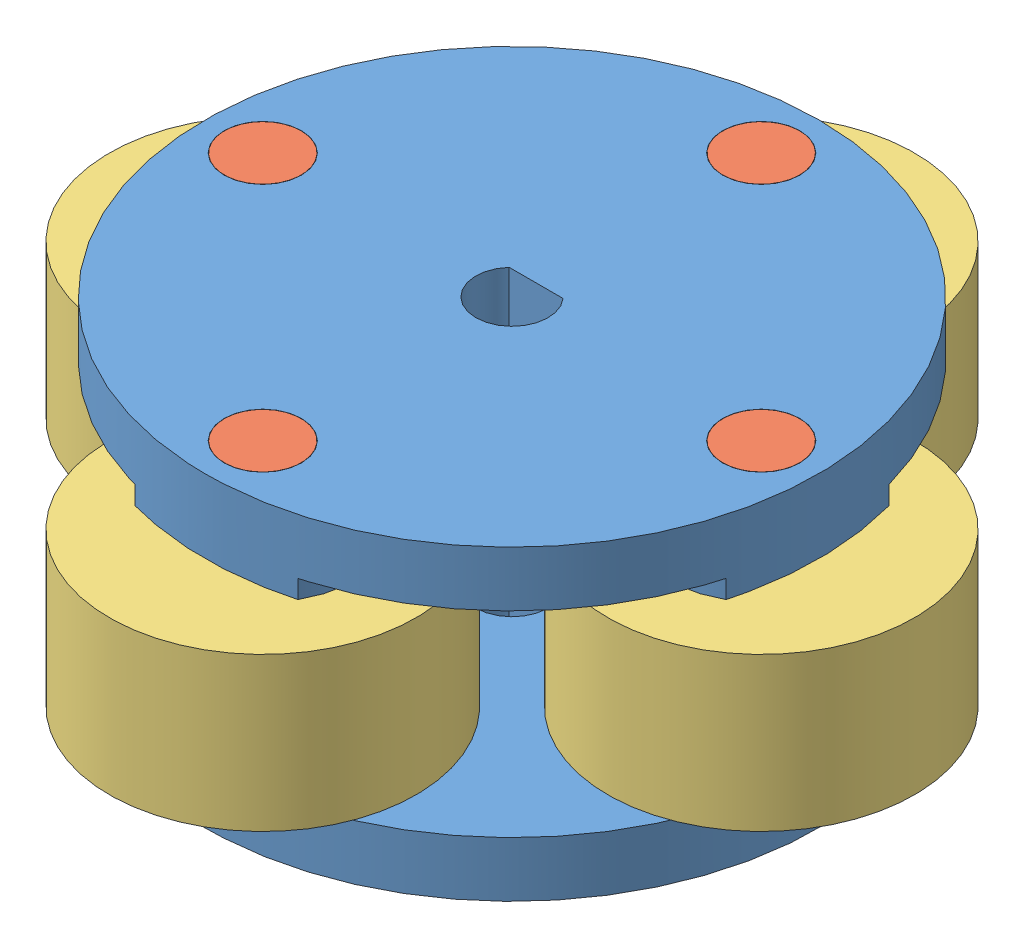
SolidWorks assembly Pump Assy, configuration Default. Lengths in mm.
Overall size (40.83 14.61 40.83).
14 component instances, 3 part files, 8 mates.
Components (placement in the parent):
- Wheel-1: Wheel [Default] at origin size (25.4 4 25.4)
- Roller Assembly-1: Roller Assembly [Default] at (-10.3187 6.35 0) x (0.813985 0 0.580886) z (-0.580886 0 0.813985) size (16.81 12.7 16.81)
  - dowel-1: dowel [Default] at origin size (3.17 12.7 3.17)
  - Sleeve Bearing-1: Sleeve Bearing [Default] x (0.980576 0 0.196139) z (-0.196139 0 0.980576) size (14.29 6.35 14.29)
- Roller Assembly-2: Roller Assembly [Default] at (0 6.35 -10.3187) x (-0.580886 0 0.813985) z (-0.813985 0 -0.580886) size (16.81 12.7 16.81)
  - dowel-1: dowel [Default] at origin size (3.17 12.7 3.17)
  - Sleeve Bearing-1: Sleeve Bearing [Default] x (0.980576 0 0.196139) z (-0.196139 0 0.980576) size (14.29 6.35 14.29)
- Roller Assembly-3: Roller Assembly [Default] at (10.3187 6.35 0) x (-0.813985 0 -0.580886) z (0.580886 0 -0.813985) size (16.81 12.7 16.81)
  - dowel-1: dowel [Default] at origin size (3.17 12.7 3.17)
  - Sleeve Bearing-1: Sleeve Bearing [Default] x (0.980576 0 0.196139) z (-0.196139 0 0.980576) size (14.29 6.35 14.29)
- Roller Assembly-4: Roller Assembly [Default] at (0 6.35 10.3187) x (0.580886 0 -0.813985) z (0.813985 0 0.580886) size (16.81 12.7 16.81)
  - dowel-1: dowel [Default] at origin size (3.17 12.7 3.17)
  - Sleeve Bearing-1: Sleeve Bearing [Default] x (0.980576 0 0.196139) z (-0.196139 0 0.980576) size (14.29 6.35 14.29)
- Wheel-2: Wheel [Default] at (0 12.7 0) x (-1 0 0) z (0 0 1) size (25.4 4 25.4)
Mates (geometry in assembly coordinates):
- Concentric1: concentric anti-aligned: cylinder of Wheel-1 through (-10.3187 0 0) axis (0 1 0) radius 1.6002; cylinder of Roller Assembly-1/dowel-1 through (-10.3187 12.7 0) axis (0 -1 0) radius 1.5875
- Coincident1: coincident aligned: plane of Wheel-1 through (0 0 0) normal (0 -1 0); plane of Roller Assembly-1/dowel-1 through (-11.611 0 -0.9222) normal (0 -1 0)
- Concentric4: concentric anti-aligned: cylinder of Wheel-1 through (0 2.286 0) axis (0 -1 0) radius 1.4986; cylinder of Wheel-2 through (0 10.414 0) axis (0 1 0) radius 1.4986
- Coincident3: coincident aligned: plane of Wheel-1 through (-1.1176 2.286 -0.9984) normal (0 0 1); plane of Wheel-2 through (1.1176 10.414 -0.9984) normal (0 0 1)
- Coincident4: coincident aligned: plane of Roller Assembly-3/dowel-1 through (11.611 12.7 0.9222) normal (0 1 0); plane of Wheel-2 through (0 12.7 0) normal (0 1 0)
- Coincident5: coincident aligned: plane of Roller Assembly-2/dowel-1 through (0.9222 12.7 -11.611) normal (0 1 0); plane of Wheel-2 through (0 12.7 0) normal (0 1 0)
- Coincident6: coincident aligned: plane of Roller Assembly-1/dowel-1 through (-11.611 12.7 -0.9222) normal (0 1 0); plane of Wheel-2 through (0 12.7 0) normal (0 1 0)
- Coincident7: coincident aligned: plane of Roller Assembly-4/dowel-1 through (-0.9222 12.7 11.611) normal (0 1 0); plane of Wheel-2 through (0 12.7 0) normal (0 1 0)
